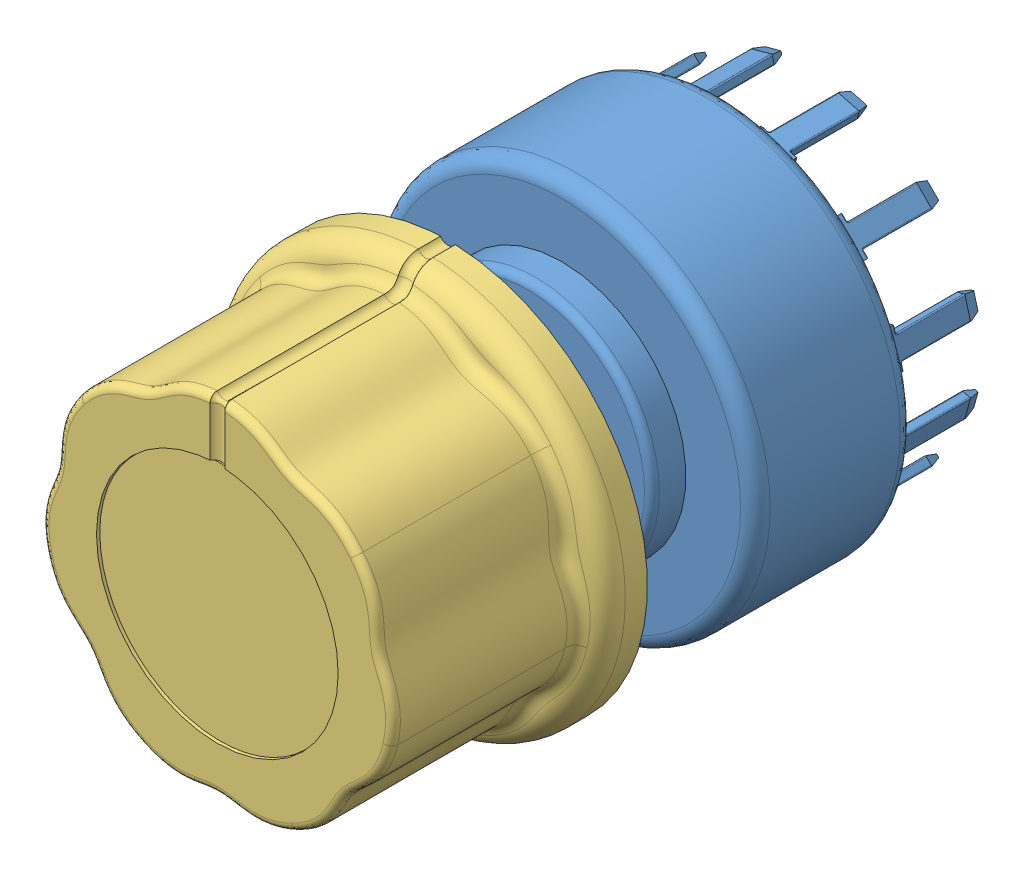
SolidWorks assembly Rotary Switch - CKF Sealed, configuration 4P-3W - 18mm. Lengths in mm.
Overall size (27 27.07 40.65).
6 component instances, 5 part files, 7 mates.
Components (placement in the parent):
- Rotary Switch - CKF Sealed-1: Rotary Switch - CKF Sealed [4P-3W Shaft 18mm] at origin size (26.2 26.2 37.5)
- hex nut jam_am-thin-1: hex nut jam_am-thin [B18.2.4.5M - Hex jam nut,  M10 x 0.75] at (0 0 5.3) x (0.999894 -0.014557 0) z (0 0 1) size (14 16.17 2.5)
- Pointer Knob WTN-15-1: Pointer Knob WTN-15 [Default] at (0 0 5.4) size (27 27.07 15.83)
  - Pointer Knob WTN-15-1: Pointer Knob WTN-15 [Default] at origin size (27 27.07 15.83)
  - socket set screw flat point_am-2: socket set screw flat point_am [B18.3.6M - M4 x 0.7 x 8 Hex Socket Flat Pt. SS --N] at (0 -10.2 7.85) x (0 1 0) z (0 0 1) size (8 4 4)
- external tooth lock washer_am-1: external tooth lock washer_am [B18.21.2M-External Tooth Lock Washers_AM10] at (0 0 2) x (-0.163951 0.986469 0) z (0 0 1) size (17 17 0.8)
Mates (geometry in assembly coordinates):
- Concentric21: concentric anti-aligned: cylinder of Rotary Switch - CKF Sealed-1 through (0 0 8) axis (0 0 -1) radius 5; cylinder of hex nut jam_am-thin-1 through (0 0 -19.7375) axis (0 0 1) radius 5
- Coincident5: coincident anti-aligned: plane of hex nut jam_am-thin-1 through (0.1177 8.082 2.8) normal (0 0 -1); plane of external tooth lock washer_am-1 through (0 0 2.8) normal (0 0 1)
- Concentric31: concentric aligned: cylinder of Rotary Switch - CKF Sealed-1 through (0 0 18) axis (0 0 -1) radius 3; cylinder of Pointer Knob WTN-15-1/Pointer Knob WTN-15-1 through (0 0 8.5) axis (0 0 -1) radius 3.2
- Parallel11: parallel anti-aligned: plane of Rotary Switch - CKF Sealed-1 through (-3 -2.2 18) normal (0 -1 0); plane of ? through (-1.4096 -4.4354 14.3384) normal (0 1 0)
- Coincident31: coincident anti-aligned: plane of Rotary Switch - CKF Sealed-1 through (0 0 18) normal (0 0 1); plane of Pointer Knob WTN-15-1/Pointer Knob WTN-15-1 through (0 0 18) normal (0 0 -1)
- Concentric4: concentric aligned: cylinder of Rotary Switch - CKF Sealed-1 through (0 0 8) axis (0 0 -1) radius 5; cylinder of external tooth lock washer_am-1 through (0 0 2.8) axis (0 0 -1) radius 5.3
- Distance2: distance = 2 mm anti-aligned: plane of external tooth lock washer_am-1 through (0 0 2) normal (0 0 -1); plane of Rotary Switch - CKF Sealed-1 through (0 0 0) normal (0 0 1)
